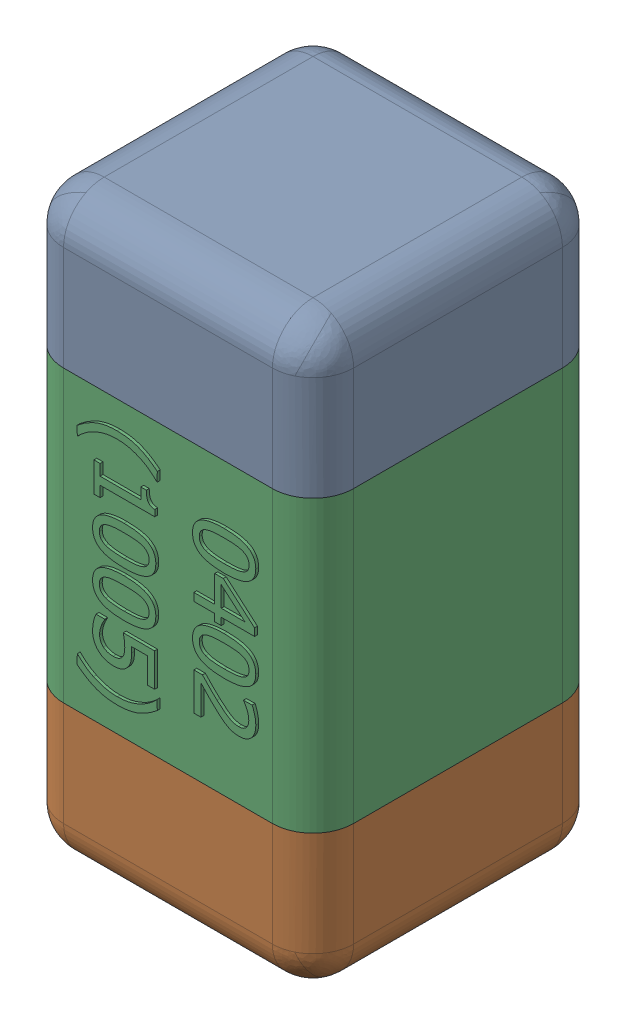
SolidWorks assembly C52, configuration Standard. Lengths in mm.
Overall size (0.51 1.01 0.51).
4 component instances, 3 part files, 0 mates.
Components (placement in the parent):
- C52-subassembly-1-1: C52-subassembly-1 [Standard] at (-6.6 -1.3001 0) x (0 -1 0) z (0 0 1) size (1.01 0.51 0.51)
  - User Library-0402_Cap-1: User Library-0402_Cap [Standard] at origin size (0.26 0.51 0.51)
  - User Library-0402_Cap-1-1: User Library-0402_Cap-1 [Standard] at origin size (0.26 0.5 0.51)
  - User Library-0402_Cap-2-1: User Library-0402_Cap-2 [Standard] at origin size (0.5 0.5 0.51)
